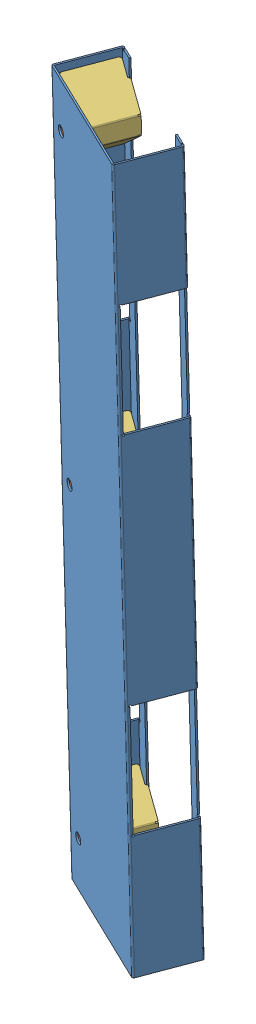
SolidWorks assembly 組合件7, configuration 預設. Lengths in mm.
Overall size (361.24 1395.13 299.03).
7 component instances, 3 part files, 8 mates.
Components (placement in the parent):
- LB-A54-01-1-1: LB-A54-01-1 [預設] at (30356.9646 -5580.7986 13953.1651) x (0.043909 0.996545 0.070494) z (-0.406822 -0.046611 0.912317) size (1380 221 100.99)
- LB-A54-01-5-1: LB-A54-01-5 [預設] at (-1035.0252 273.7156 249.5182) x (0.043909 0.996545 0.070494) z (-0.406822 -0.046611 0.912317) size (134 50 4)
- LB-A54-01-5-2: LB-A54-01-5 [預設] at (-1008.6798 871.6428 291.8149) x (0.043909 0.996545 0.070494) z (-0.406822 -0.046611 0.912317) size (134 50 4)
- LB-A54-01-5-3: LB-A54-01-5 [預設] at (-982.3344 1469.57 334.1115) x (0.043909 0.996545 0.070494) z (-0.406822 -0.046611 0.912317) size (134 50 4)
- LB-A54-01-4-1: LB-A54-01-4 [預設] at (-1029.6546 1468.705 317.3507) x (0.676249 0.656059 0.335073) z (-0.614152 0.753269 -0.235379) size (105.23 97 105.23)
- LB-A54-01-4-2: LB-A54-01-4 [預設] at (-1056 870.7778 275.054) x (0.676249 0.656059 0.335073) z (-0.614152 0.753269 -0.235379) size (105.23 97 105.23)
- LB-A54-01-4-3: LB-A54-01-4 [預設] at (-1082.3453 272.8506 232.7573) x (0.676249 0.656059 0.335073) z (-0.614152 0.753269 -0.235379) size (105.23 97 105.23)
Mates (geometry in assembly coordinates):
- 重合/共線/共點1: coincident anti-aligned: plane of LB-A54-01-1-1 through (-1132.641 1637.5609 280.0538) normal (0.406822 0.046611 -0.912317); plane of LB-A54-01-5-1 through (-1032.9642 357.239 259.089) normal (-0.406822 -0.046611 0.912317)
- 同軸心1: concentric aligned: cylinder of LB-A54-01-1-1; cylinder of LB-A54-01-5-1
- 平行1: parallel: plane of LB-A54-01-1-1 through (-976.3103 1634.9386 219.7509) normal (0.912451 -0.068738 0.40337); line of LB-A54-01-5-1
- 重合/共線/共點6: coincident anti-aligned: plane of LB-A54-01-1-1 through (-1132.641 1637.5609 280.0538) normal (0.406822 0.046611 -0.912317); plane of LB-A54-01-4-1 through (-976.5079 1555.3836 345.4784) normal (-0.406822 -0.046611 0.912317)
- 重合/共線/共點7: coincident: plane of LB-A54-01-1-1 through (-976.3103 1634.9386 219.7509) normal (0.912451 -0.068738 0.40337); line of LB-A54-01-4-1
- 重合/共線/共點8: coincident: plane of LB-A54-01-1-1 through (-976.3103 1634.9386 219.7509) normal (0.912451 -0.068738 0.40337); line of LB-A54-01-4-1
- 重合/共線/共點11: coincident: unknown of LB-A54-01-1-1; point of LB-A54-01-4-1
- 局部直線複製2: unknown: unknown of LB-A54-01-1-1
